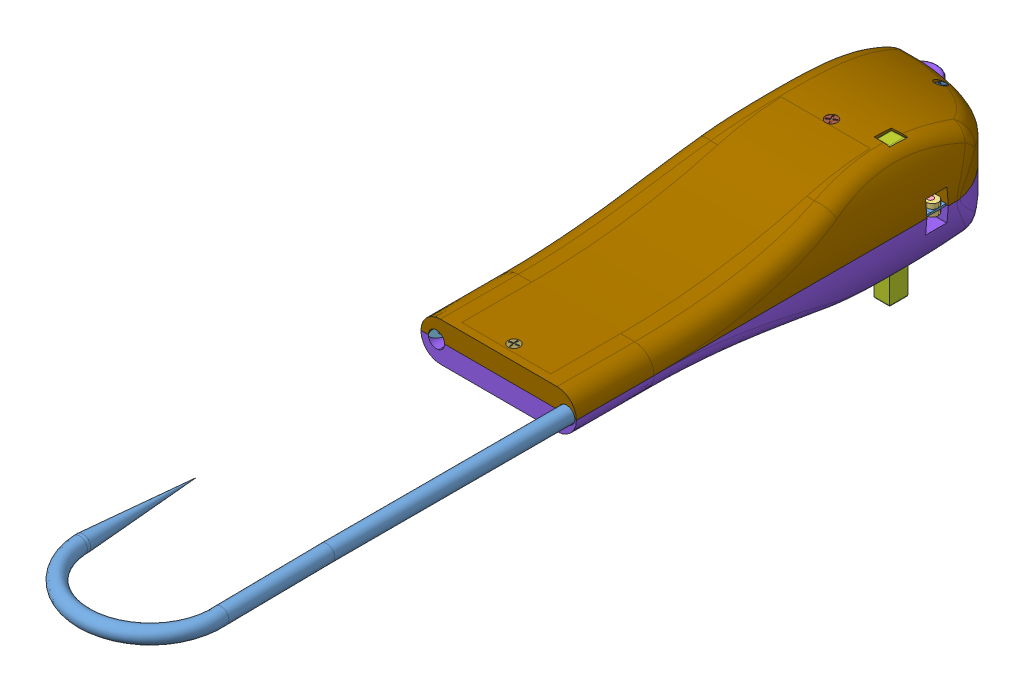
SolidWorks assembly Assem1, configuration Default. Lengths in mm.
Overall size (21.64 18.49 118.14).
12 component instances, 12 part files, 25 mates.
Components (placement in the parent):
- Style2-1(Hook)-1: Style2-1(Hook) [Default] at (43.0137 34.2394 68.5249) x (-0.000617 0 1) z (-1 0 -0.000617) size (102.8 2.14 19.28)
- Style 2-1(Pivot)-1: Style 2-1(Pivot) [Default] at (28.3255 34.2394 22.004) x (-0.997424 0 0.071727) z (-0.071727 0 -0.997424) size (0.5 10 0.5)
- Style 2-1 (ConnectingRod)-2: Style 2-1 (ConnectingRod) [Default] at (35.809 33.4894 21.5062) x (0.066377 0 0.997795) z (-0.997795 0 0.066377) size (1.5 1.5 16.5)
- Style 2-1(Pin)-2: Style 2-1(Pin) [Default] at (43.043 34.2394 21.0249) x (-0.851629 0 0.524145) z (-0.524145 0 -0.851629) size (0.75 1.5 0.75)
- SpringTrigger-2: SpringTrigger [Default] at (24.0709 33.8644 21.2835) x (1 0 0.000617) z (0 1 0) size (4.5 49 2.75)
- Spring2-3: Spring2 [Neutral] at (26.3335 34.2394 9.0028) x (-0.923728 -0.383049 -0.00057) z (-0.383049 0.923728 -0.000236) size (1.55 40.92 1.73)
- Safety-1: Safety [Default] at (39.1357 31.9119 22.2104) x (0 1 0) z (-1 0 -0.000617) size (17.78 2.84 2)
- BaseFinale-1: BaseFinale [Default] at (34.3343 34.2394 7.7577) x (1 0 0.000617) z (-0.000617 0 1) size (20.37 9.34 63.07)
- CoverFinale-1: CoverFinale [Default] at (34.3343 34.2394 7.7577) x (1 0 0.000617) z (-0.000617 0 1) size (20.37 9.34 61.15)
- Screw3-1: Screw3 [Default] at (34.301 35.2893 10.9827) x (0.569121 0 -0.822254) z (0 -1 0) size (1.43 1.43 5.25)
- Screw2-1: Screw2 [Default] at (34.2924 36.9894 24.9836) x (0.850471 0 -0.526022) z (0 -1 0) size (1.5 1.5 8.45)
- Screw-1: Screw [Default] at (34.2672 34.615 65.7577) x (0.144503 0 0.989504) z (0 -1 0) size (1.5 1.5 4.01)
Mates (geometry in assembly coordinates):
- Concentric10: concentric anti-aligned: cylinder of Style 2-1(Pivot)-1 through (28.3255 34.9894 22.004) axis (0 -1 0) radius 0.25; cylinder of Style 2-1 (ConnectingRod)-2 through (28.3255 31.9894 22.004) axis (0 1 0) radius 0.25
- Concentric14: concentric aligned: cylinder of Style2-1(Hook)-1 through (43.043 33.235 21.0249) axis (0 1 0) radius 0.375; cylinder of Style 2-1 (ConnectingRod)-2 through (43.043 33.4884 21.0249) axis (0 1 0) radius 0.375
- Concentric15: concentric anti-aligned: cylinder of Style2-1(Hook)-1 through (43.043 33.235 21.0249) axis (0 1 0) radius 0.375; cylinder of Style 2-1(Pin)-2 through (43.043 34.3644 21.0249) axis (0 -1 0) radius 0.375
- Concentric23: concentric aligned: line of Spring2-3 through (26.3335 34.2394 9.0028) axis (-0.000617 0 1); cylinder of SpringTrigger-2 through (26.3283 34.2394 17.4565) axis (-0.000617 0 1) radius 1
- Coincident40: coincident: plane of Style 2-1 (ConnectingRod)-2 through (35.809 33.4894 21.5062) normal (0 -1 0); line of SpringTrigger-2 through (27.5716 33.4894 20.2857) axis (-0.000617 0 1)
- Coincident41: coincident anti-aligned: plane of Style2-1(Hook)-1 through (42.0436 34.1144 20.0243) normal (0 -1 0); plane of Style 2-1 (ConnectingRod)-2 through (43.3422 34.1144 21.7567) normal (0 1 0)
- Coincident42: coincident aligned: plane of Style 2-1 (ConnectingRod)-2 through (35.809 33.4894 21.5062) normal (0 -1 0); plane of Style 2-1(Pin)-2 through (43.043 33.4894 21.0249) normal (0 -1 0)
- Coincident50: coincident anti-aligned: plane of Spring2-3 through (26.7307 34.4041 9.003) normal (0.000617 0 -1); plane of BaseFinale-1 through (26.3335 34.2394 9.0028) normal (-0.000617 0 1)
- Concentric25: concentric anti-aligned: cylinder of BaseFinale-1 through (34.301 32.7394 10.9827) axis (0 1 0) radius 0.465; cylinder of CoverFinale-1 through (34.301 35.7394 10.9827) axis (0 -1 0) radius 0.465
- Concentric26: concentric anti-aligned: cylinder of BaseFinale-1 through (34.2672 32.7394 65.7577) axis (0 1 0) radius 0.5; cylinder of CoverFinale-1 through (34.2672 35.7394 65.7577) axis (0 -1 0) radius 0.5
- Coincident51: coincident anti-aligned: plane of BaseFinale-1 through (39.9854 34.2394 66.7612) normal (0 1 0); plane of CoverFinale-1 through (39.9854 34.2394 66.7612) normal (0 -1 0)
- Concentric27: concentric anti-aligned: cylinder of CoverFinale-1 through (34.301 35.7394 10.9827) axis (0 -1 0) radius 0.465; cylinder of Screw3-1 through (34.301 32.7893 10.9827) axis (0 1 0) radius 0.465
- Concentric30: concentric anti-aligned: cylinder of CoverFinale-1 through (34.2924 35.7394 24.9836) axis (0 -1 0) radius 0.5; cylinder of Screw2-1 through (34.2924 32.8894 24.9836) axis (0 1 0) radius 0.5
- Concentric31: concentric anti-aligned: cylinder of CoverFinale-1 through (34.301 35.7394 10.9827) axis (0 -1 0) radius 0.465; cylinder of Screw3-1 through (34.301 32.7893 10.9827) axis (0 1 0) radius 0.465
- Coincident53: coincident aligned: cone of CoverFinale-1 through (34.301 38.0394 10.9827) axis (0 -1 0); cone of Screw3-1 through (34.301 38.0393 10.9827) axis (0 -1 0)
- Concentric34: concentric anti-aligned: cylinder of CoverFinale-1 through (34.2924 35.7394 24.9836) axis (0 -1 0) radius 0.5; cylinder of Screw2-1 through (34.2924 32.8894 24.9836) axis (0 1 0) radius 0.5
- Concentric36: concentric anti-aligned: cylinder of CoverFinale-1 through (34.2672 35.7394 65.7577) axis (0 -1 0) radius 0.5; cylinder of Screw-1 through (34.2672 32.735 65.7577) axis (0 1 0) radius 0.5
- Tangent2: tangent: face of CoverFinale-1; plane of Screw-1 through (33.5251 36.745 65.8661) normal (0 1 0)
- Coincident55: coincident aligned: cone of CoverFinale-1 through (34.2924 41.3394 24.9836) axis (0 -1 0); cone of Screw2-1 through (34.2924 41.3394 24.9836) axis (0 -1 0)
- Concentric39: concentric anti-aligned: cylinder of Style 2-1(Pivot)-1 through (28.3255 34.9894 22.004) axis (0 -1 0) radius 0.25; circle of CoverFinale-1
- Parallel5: parallel anti-aligned: plane of SpringTrigger-2 through (24.0709 33.4894 21.2835) normal (0 -1 0); plane of BaseFinale-1 through (44.325 32.2394 22.7639) normal (0 1 0)
- Coincident64: coincident anti-aligned: plane of Safety-1 through (39.0116 41.1619 24.2365) normal (-1 0 -0.000617); plane of CoverFinale-1 through (39.013 44.2394 22.0365) normal (1 0 0.000617)
- Coincident65: coincident anti-aligned: plane of Safety-1 through (41.0116 41.1619 24.2378) normal (-0.000617 0 1); plane of BaseFinale-1 through (39.0116 24.2394 24.2365) normal (0.000617 0 -1)
- Coincident66: coincident aligned: plane of Style 2-1(Pivot)-1 through (28.3255 39.2394 22.004) normal (0 1 0); circle of CoverFinale-1
- Concentric40: concentric aligned: cylinder of BaseFinale-1 through (26.3335 34.2394 9.0028) axis (-0.000617 0 1) radius 0.75; line of Spring2-3 through (26.3335 34.2394 9.0028) axis (-0.000617 0 1)
